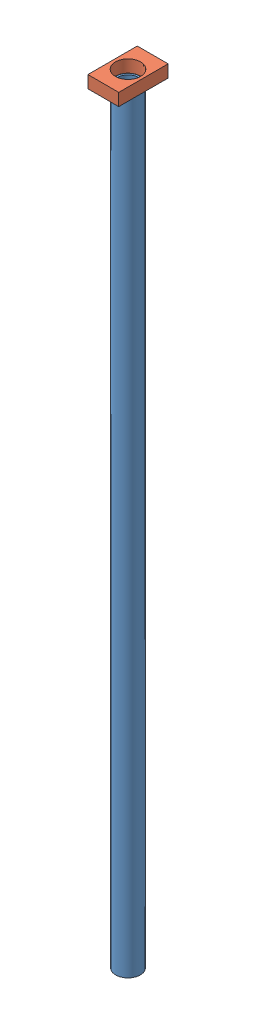
SolidWorks assembly NikeLimboRound, configuration Default. Lengths in mm.
Overall size (50 1260 80).
2 component instances, 2 part files, 2 mates.
Components (placement in the parent):
- FrameRound-1: FrameRound [Default] at (-32.8321 0 -17.7921) size (40 1240 40)
- MountRound-1: MountRound [Default] at (-15.04 -1255.4077 -50.6242) x (0 0 -1) z (1 0 0) size (80 20 50)
Mates (geometry in assembly coordinates):
- Concentric1: concentric aligned: cylinder of FrameRound-1 through (-32.8321 1240 -17.7921) axis (0 -1 0) radius 20; cylinder of MountRound-1 through (-32.8321 1260.001 -17.7921) axis (0 -1 0) radius 20.5
- Parallel1: parallel aligned: plane of MountRound-1 through (-7.8321 1260 22.2079) normal (0 0 1); plane of assembly through (0 0 0) normal (0 0 1)
